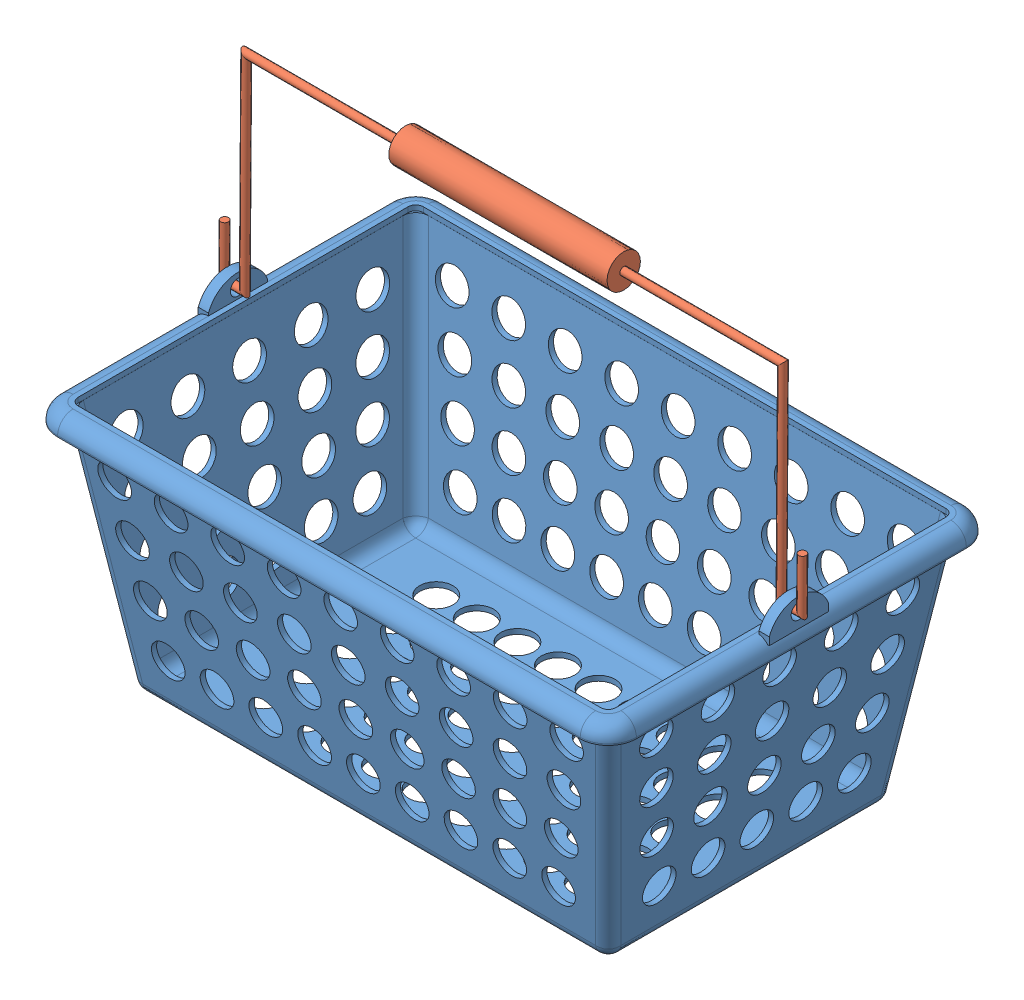
SolidWorks assembly BasketAssembly2, configuration Default. Lengths in mm.
Overall size (228 187.54 150.83).
2 component instances, 2 part files, 7 mates.
Components (placement in the parent):
- Basket-1: Basket [Default] at origin size (225.83 106 150.83)
- Handle2-1: Handle2 [Default] at (0.4478 180.9981 -0.5552) x (1 0 0) z (0 -0.999976 0.00694) size (228 13 88)
Mates (geometry in assembly coordinates):
- Concentric1: concentric anti-aligned: circle of Basket-1; cylinder of Handle-1 through (116.5055 100.985 0) axis (-1 0 0) radius 1.5
- Parallel1: parallel anti-aligned: cylinder of Basket-1 through (-101.6978 101 0) axis (-1 0 0) radius 3; cylinder of Handle-1 through (-111.9945 100.985 0) axis (1 0 0) radius 1.5
- Concentric8: concentric anti-aligned: cylinder of Basket-1 through (-101.6978 101 0) axis (-1 0 0) radius 3; cylinder of Handle-2 through (-113.9478 101 0) axis (1 0 0) radius 1.5
- Distance1: distance = 2.5 mm: cylinder of Handle-2 through (-104.1978 99.25 0.0008) axis (0 1 -0.000461) radius 1.5; plane of Basket-1 through (-106.6978 95 11.5) normal (1 0 0)
- Concentric9: concentric anti-aligned: cylinder of Basket-1 through (-101.6978 101 0) axis (-1 0 0) radius 3; cylinder of Handle2-1 through (-113.8022 101 0) axis (1 0 0) radius 1.5
- Parallel2: parallel anti-aligned: cylinder of Basket-1 through (102.6978 100.985 0) axis (1 0 0) radius 3; cylinder of Handle2-1 through (114.6978 101 0) axis (-1 0 0) radius 1.5
- Distance2: distance = 2.75 mm: plane of Basket-1 through (107.6978 95 11.5) normal (-1 0 0); cylinder of Handle2-1 through (104.9478 99.25 0.0121) axis (0 0.999976 -0.00694) radius 1.5
